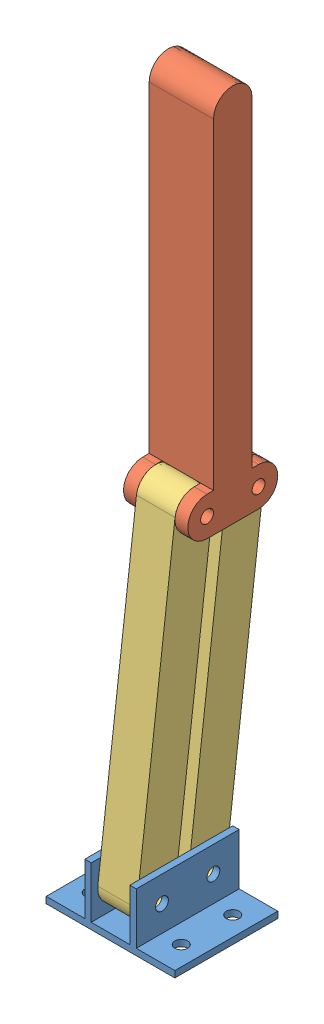
SolidWorks assembly Arm Assem, configuration Default. Lengths in mm.
Overall size (63.5 351.28 67.77).
4 component instances, 3 part files, 7 mates.
Components (placement in the parent):
- Mounting Bracket-1: Mounting Bracket [Default] at origin size (63.5 28.57 50.8)
- Contact Arm-1: Contact Arm [Default] at (15.875 173.4753 -6.3712) x (0 1 0) z (1 0 0) size (187.33 44.45 31.75)
- Parallel Arm-2: Parallel Arm [Default] at (41.275 94.6751 28.5644) x (0 0.992758 -0.120134) z (0 0.120134 0.992758) size (177.8 19.05 19.05)
- Parallel Arm-3: Parallel Arm [Default] at (41.275 94.6751 3.1644) x (0 0.992758 -0.120134) z (0 0.120134 0.992758) size (177.8 19.05 19.05)
Mates (geometry in assembly coordinates):
- Concentric1: concentric: cylinder of Mounting Bracket-1 through (63.5 15.875 12.7) axis (-1 0 0) radius 3.175; cylinder of Parallel Arm-3 through (22.225 15.875 12.7) axis (1 0 0) radius 3.175
- Coincident1: coincident: plane of Mounting Bracket-1 through (41.275 28.575 50.8) normal (-1 0 0); plane of Parallel Arm-3 through (41.275 15.875 12.7) normal (1 0 0)
- Concentric2: concentric: cylinder of Mounting Bracket-1 through (63.5 15.875 38.1) axis (-1 0 0) radius 3.175; cylinder of Parallel Arm-2 through (22.225 15.875 38.1) axis (1 0 0) radius 3.175
- Coincident2: coincident: plane of Mounting Bracket-1 through (22.225 3.175 50.8) normal (1 0 0); plane of Parallel Arm-2 through (22.225 15.875 38.1) normal (-1 0 0)
- Concentric4: concentric: cylinder of Contact Arm-1 through (47.625 173.4753 -6.3712) axis (-1 0 0) radius 3.175; cylinder of Parallel Arm-3 through (22.225 173.4753 -6.3712) axis (1 0 0) radius 3.175
- Coincident3: coincident: plane of Contact Arm-1 through (22.225 183.0003 -6.3712) normal (1 0 0); plane of Parallel Arm-3 through (22.225 15.875 12.7) normal (-1 0 0)
- Concentric5: concentric: cylinder of Contact Arm-1 through (47.625 173.4753 19.0288) axis (-1 0 0) radius 3.175; cylinder of Parallel Arm-2 through (22.225 173.4753 19.0288) axis (1 0 0) radius 3.175
